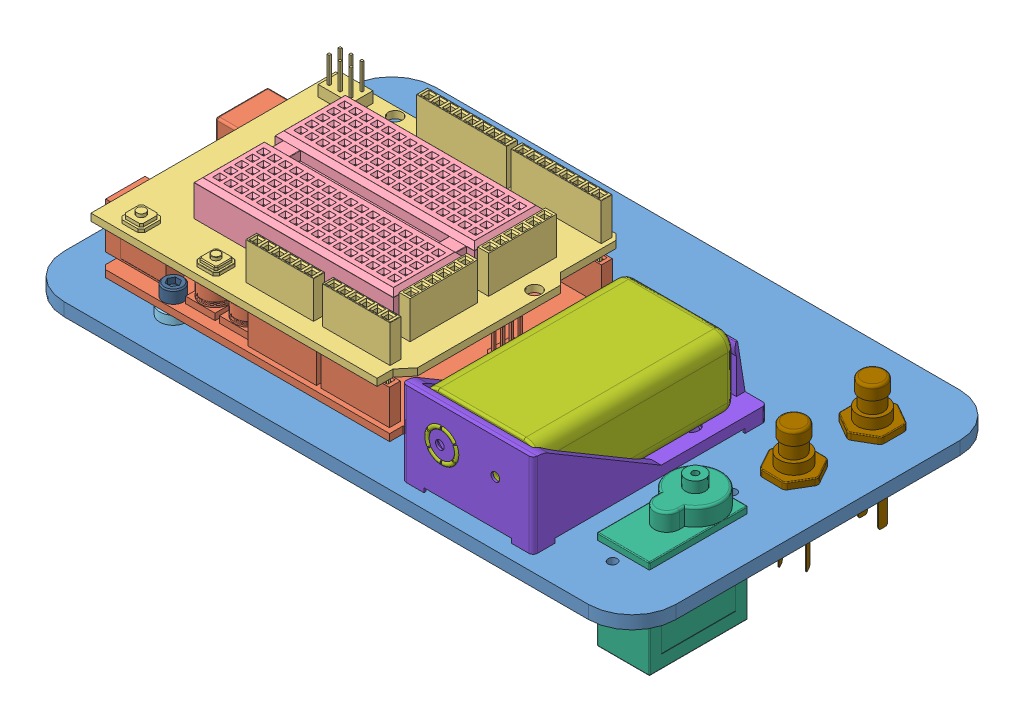
SolidWorks assembly Portable_servo, configuration Default. Lengths in mm.
Overall size (140 45.27 85).
18 component instances, 10 part files, 38 mates.
Components (placement in the parent):
- Side-1: Side [Servo mount piece] at (30.5695 53.7577 78.2373) size (140 3 85)
- ArduinoUno-1: ArduinoUno [Default] at (4.5695 58.7577 86.5873) size (74.8 12.1 53.3)
- Prototyping Shield-1: Prototyping Shield [Default] at (24.1989 35.8415 143.5707) x (-1 0 0) z (0 0 -1) size (68 18.92 56)
  - Arduino Prototyping Shield-1: Arduino Prototyping Shield [Default] at (18.3696 35.0162 55.7334) size (68 18.92 56)
  - MiniBreadboard-1: MiniBreadboard [Default] at (16.6696 36.6462 55.7334) x (0 0 1) z (-1 0 0) size (34.6 8.15 45.6)
- Washer-1: Washer [Default] at (-12.8305 56.7577 62.4373) x (0.932226 0 0.361876) z (-0.361876 0 0.932226) size (6.2 2 6.2)
- Washer-2: Washer [Default] at (-14.4305 56.7577 110.7373) x (0.936099 0 0.351737) z (-0.351737 0 0.936099) size (6.2 2 6.2)
- Washer-3: Washer [Default] at (37.9695 56.7577 77.7373) x (-0.253842 0 0.967246) z (-0.967246 0 -0.253842) size (6.2 2 6.2)
- Washer-4: Washer [Default] at (37.9695 56.7577 105.6373) size (6.2 2 6.2)
- Micro Servo FS90R Continuous-1: Micro Servo FS90R Continuous [Valor predeterminado] at (84.7695 51.7577 95.7373) x (0 0 1) z (-1 0 0) size (32 29 12)
- 9V Battery 2-1: 9V Battery 2 [Default] at (61.2747 82.0732 77.0513) x (1 0 0) z (0 -1 0) size (25.91 48.13 16.26)
- 9V Battery Holder-1: 9V Battery Holder [Default] at (59.6094 57.7577 90.6915) x (0 0 -1) z (0 1 0) size (53.5 30 19.31)
- Panel Mount Pushbutton-1: Panel Mount Pushbutton [Default] at (87.5695 45.6327 70.7373) x (0.872416 0 -0.488764) z (0.488764 0 0.872416) size (9.91 29 11.13)
- Panel Mount Pushbutton-2: Panel Mount Pushbutton [Default] at (87.5695 45.6327 52.7373) size (9.91 29 11.13)
- socket head cap screw_ai-2: socket head cap screw_ai [HX-SHCS 0.112-40x0.375x0.375-N] at (-12.8305 63.2025 62.4373) x (0 -1 0) z (0 0 1) size (12.37 4.65 4.65)
- socket head cap screw_ai-3: socket head cap screw_ai [HX-SHCS 0.112-40x0.375x0.375-N] at (37.9695 63.2025 105.6373) x (0 -1 0) z (0 0 1) size (12.37 4.65 4.65)
- socket head cap screw_ai-4: socket head cap screw_ai [HX-SHCS 0.112-40x0.375x0.375-N] at (-14.4305 63.2025 110.7373) x (0 -1 0) z (0 0 1) size (12.37 4.65 4.65)
- socket head cap screw_ai-5: socket head cap screw_ai [HX-SHCS 0.112-40x0.375x0.375-N] at (37.9695 61.6025 77.7373) x (0 -1 0) z (-0.804692 0 0.593692) size (12.37 4.65 4.65)
Mates (geometry in assembly coordinates):
- Coincident4: coincident anti-aligned: plane of ArduinoUno-1 through (35.1693 68.3577 110.3373) normal (0 0 1); plane of Prototyping Shield-1/Arduino Prototyping Shield-1 through (34.9193 62.1077 110.3373) normal (0 0 -1)
- Width1: width anti-aligned: plane of Prototyping Shield-1/Arduino Prototyping Shield-1 through (34.9193 62.1077 110.3373) normal (1 0 0); plane of Prototyping Shield-1/Arduino Prototyping Shield-1 through (34.4193 62.1077 110.3373) normal (-1 0 0); plane of ArduinoUno-1 through (35.1693 68.3577 111.3373) normal (-1 0 0); plane of ArduinoUno-1 through (34.1693 68.3577 111.3373) normal (1 0 0)
- Coincident5: coincident anti-aligned: plane of ArduinoUno-1 through (-34.6305 70.8577 80.9373) normal (0 1 0); plane of Prototyping Shield-1/Arduino Prototyping Shield-1 through (-28.1707 70.8577 59.8373) normal (0 -1 0)
- Concentric1: concentric anti-aligned: cylinder of Side-1 through (37.9695 53.7577 105.6373) axis (0 1 0) radius 1.6; cylinder of ArduinoUno-1 through (37.9695 60.3577 105.6373) axis (0 -1 0) radius 1.6
- Concentric2: concentric anti-aligned: cylinder of Side-1 through (-12.8305 53.7577 62.4373) axis (0 1 0) radius 1.6; cylinder of ArduinoUno-1 through (-12.8305 60.3577 62.4373) axis (0 -1 0) radius 1.6
- Concentric3: concentric anti-aligned: cylinder of Side-1 through (37.9695 53.7577 105.6373) axis (0 1 0) radius 1.6; cylinder of Washer-4 through (37.9695 58.7577 105.6373) axis (0 -1 0) radius 1.6
- Coincident6: coincident anti-aligned: plane of Side-1 through (30.5695 56.7577 78.2373) normal (0 1 0); plane of Washer-4 through (37.9695 56.7577 105.6373) normal (0 -1 0)
- Coincident7: coincident anti-aligned: plane of ArduinoUno-1 through (37.5695 58.7577 59.9373) normal (0 -1 0); plane of Washer-4 through (37.9695 58.7577 105.6373) normal (0 1 0)
- Concentric4: concentric anti-aligned: cylinder of Side-1 through (37.9695 53.7577 77.7373) axis (0 1 0) radius 1.6; cylinder of Washer-3 through (37.9695 58.7577 77.7373) axis (0 -1 0) radius 1.6
- Coincident8: coincident anti-aligned: plane of Side-1 through (30.5695 56.7577 78.2373) normal (0 1 0); plane of Washer-3 through (37.9695 56.7577 77.7373) normal (0 -1 0)
- Concentric5: concentric anti-aligned: cylinder of Side-1 through (-14.4305 53.7577 110.7373) axis (0 1 0) radius 1.6; cylinder of Washer-2 through (-14.4305 58.7577 110.7373) axis (0 -1 0) radius 1.6
- Coincident9: coincident anti-aligned: plane of Side-1 through (30.5695 56.7577 78.2373) normal (0 1 0); plane of Washer-2 through (-14.4305 56.7577 110.7373) normal (0 -1 0)
- Concentric6: concentric anti-aligned: cylinder of Side-1 through (-12.8305 53.7577 62.4373) axis (0 1 0) radius 1.6; cylinder of Washer-1 through (-12.8305 58.7577 62.4373) axis (0 -1 0) radius 1.6
- Coincident10: coincident anti-aligned: plane of Side-1 through (30.5695 56.7577 78.2373) normal (0 1 0); plane of Washer-1 through (-12.8305 56.7577 62.4373) normal (0 -1 0)
- Coincident15: coincident anti-aligned: plane of Side-1 through (30.5695 56.7577 78.2373) normal (0 1 0); plane of 9V Battery Holder-1 through (48.8094 56.7577 90.6915) normal (0 -1 0)
- Coincident22: coincident anti-aligned: plane of Side-1 through (30.5695 53.7577 78.2373) normal (0 -1 0); plane of Micro Servo FS90R Continuous-1 through (84.7695 53.7577 109.3623) normal (0 1 0)
- Concentric12: concentric anti-aligned: cylinder of ArduinoUno-1 through (-12.8305 60.3577 62.4373) axis (0 -1 0) radius 1.6; cylinder of socket head cap screw_ai-2 through (-12.8305 94.9525 62.4373) axis (0 1 0) radius 2.3241
- Coincident23: coincident anti-aligned: plane of ArduinoUno-1 through (37.5695 60.3577 59.9373) normal (0 1 0); plane of socket head cap screw_ai-2 through (-10.5064 60.3577 62.4373) normal (0 -1 0)
- Concentric13: concentric anti-aligned: cylinder of ArduinoUno-1 through (37.9695 60.3577 105.6373) axis (0 -1 0) radius 1.6; cylinder of socket head cap screw_ai-3 through (37.9695 94.9525 105.6373) axis (0 1 0) radius 2.3241
- Coincident24: coincident anti-aligned: plane of ArduinoUno-1 through (37.5695 60.3577 59.9373) normal (0 1 0); plane of socket head cap screw_ai-3 through (40.2936 60.3577 105.6373) normal (0 -1 0)
- Concentric14: concentric anti-aligned: cylinder of ArduinoUno-1 through (-14.4305 60.3577 110.7373) axis (0 -1 0) radius 1.6; cylinder of socket head cap screw_ai-4 through (-14.4305 94.9525 110.7373) axis (0 1 0) radius 2.3241
- Coincident25: coincident anti-aligned: plane of ArduinoUno-1 through (37.5695 60.3577 59.9373) normal (0 1 0); plane of socket head cap screw_ai-4 through (-12.1064 60.3577 110.7373) normal (0 -1 0)
- Concentric15: concentric anti-aligned: cylinder of Washer-3 through (37.9695 58.7577 77.7373) axis (0 -1 0) radius 3.1; cylinder of socket head cap screw_ai-5 through (37.9695 93.3525 77.7373) axis (0 1 0) radius 2.3241
- Coincident26: coincident anti-aligned: plane of Washer-3 through (37.9695 58.7577 77.7373) normal (0 1 0); plane of socket head cap screw_ai-5 through (39.3493 58.7577 79.6075) normal (0 -1 0)
- Parallel3: parallel anti-aligned: plane of Side-1 through (30.5695 56.7577 78.2373) normal (0 1 0); plane of Micro Servo FS90R Continuous-1 through (84.7695 51.7577 109.3623) normal (0 -1 0)
- Parallel4: parallel anti-aligned: line of Side-1 through (100.5695 56.7577 45.7373) axis (0 0 1); line of Micro Servo FS90R Continuous-1 through (90.5695 58.2577 106.7873) axis (0 0 -1)
- Parallel5: parallel aligned: line of Side-1 through (-29.4305 56.7577 120.7373) axis (1 0 0); line of Micro Servo FS90R Continuous-1 through (78.9695 58.2577 106.7873) axis (1 0 0)
- Concentric17: concentric aligned: cylinder of Side-1 through (84.7695 56.7577 109.3623) axis (0 -1 0) radius 1; cylinder of Micro Servo FS90R Continuous-1 through (84.7695 53.7577 109.3623) axis (0 -1 0) radius 1
- Coincident30: coincident anti-aligned: plane of Side-1 through (30.5695 56.7577 78.2373) normal (0 1 0); plane of Panel Mount Pushbutton-2 through (87.5695 56.7577 52.7373) normal (0 -1 0)
- Coincident31: coincident anti-aligned: plane of Side-1 through (30.5695 56.7577 78.2373) normal (0 1 0); plane of Panel Mount Pushbutton-1 through (87.5695 56.7577 70.7373) normal (0 -1 0)
- Concentric18: concentric anti-aligned: cylinder of Side-1 through (87.5695 53.7577 70.7373) axis (0 1 0) radius 3.5; cylinder of Panel Mount Pushbutton-1 through (87.5695 45.6327 70.7373) axis (0 -1 0) radius 3.43
- Concentric19: concentric anti-aligned: cylinder of Side-1 through (87.5695 53.7577 52.7373) axis (0 1 0) radius 3.5; cylinder of Panel Mount Pushbutton-2 through (87.5695 45.6327 52.7373) axis (0 -1 0) radius 3.43
- Parallel6: parallel aligned: line of Side-1 through (-29.4305 56.7577 120.7373) axis (1 0 0); line of 9V Battery Holder-1 through (49.6094 57.7577 117.4415) axis (1 0 0)
- Concentric20: concentric aligned: cylinder of Side-1 through (70.3094 53.7577 104.4415) axis (0 1 0) radius 1.6; cylinder of 9V Battery Holder-1 through (70.3094 60.0691 104.4415) axis (0 1 0) radius 1.4
- Concentric22: concentric aligned: cylinder of Side-1 through (70.3094 53.7577 76.9415) axis (0 1 0) radius 1.6; cylinder of 9V Battery Holder-1 through (70.3094 60.0691 76.9415) axis (0 1 0) radius 1.4
- Coincident34: coincident anti-aligned: plane of 9V Battery 2-1 through (61.2747 60.0691 77.0513) normal (0 -1 0); plane of 9V Battery Holder-1 through (59.6094 60.0691 90.6915) normal (0 1 0)
- Tangent3: tangent anti-aligned: cylinder of 9V Battery 2-1 through (66.4132 68.1971 114.1475) axis (0 0 -1) radius 2.921; plane of 9V Battery Holder-1 through (69.8565 68.3191 112.1301) normal (-0.866025 0.5 0)
- Coincident35: coincident aligned: circle of 9V Battery 2-1; plane of 9V Battery Holder-1 through (74.6094 60.0691 116.9415) normal (0 0 -1)
